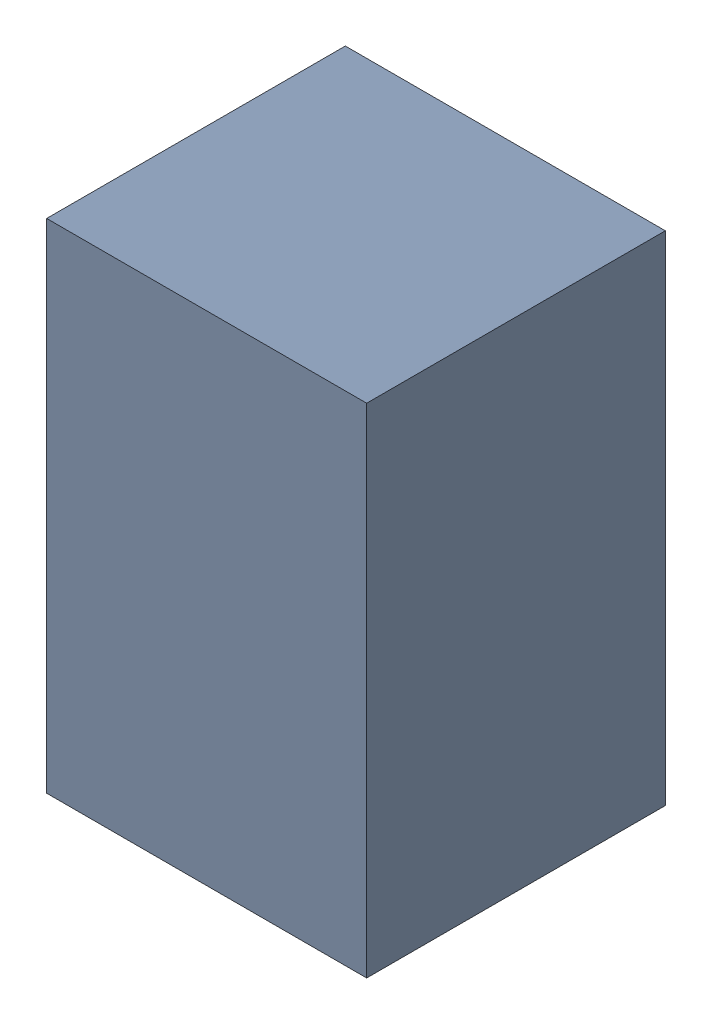
SolidWorks assembly C1_1, configuration Default. Lengths in mm.
Overall size (1.35 2.1 1.26).
2 component instances, 1 part files, 0 mates.
Components (placement in the parent):
- 407985696_1-1: 407985696_1 [Default] at (33.655 17.2596 0.0127) size (1.35 2.1 1.26)
  - Extruded_6-1: Extruded_6 [Default] at origin size (1.35 2.1 1.26)
